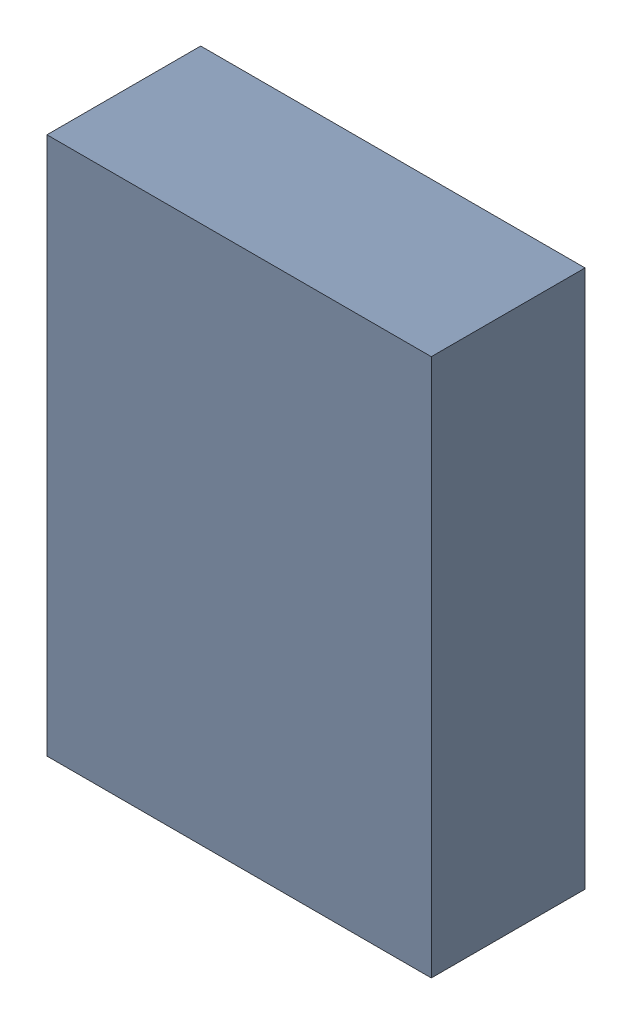
SolidWorks assembly U5Kanaloa_v2.0.0_Motor, configuration Default. Lengths in mm.
Overall size (2.5 3.5 1).
2 component instances, 1 part files, 0 mates.
Components (placement in the parent):
- 352878416-1: 352878416 [Default] at (91.344 108.701 0.05) size (2.5 3.5 1)
  - Extruded-1: Extruded [Default] at origin size (2.5 3.5 1)
